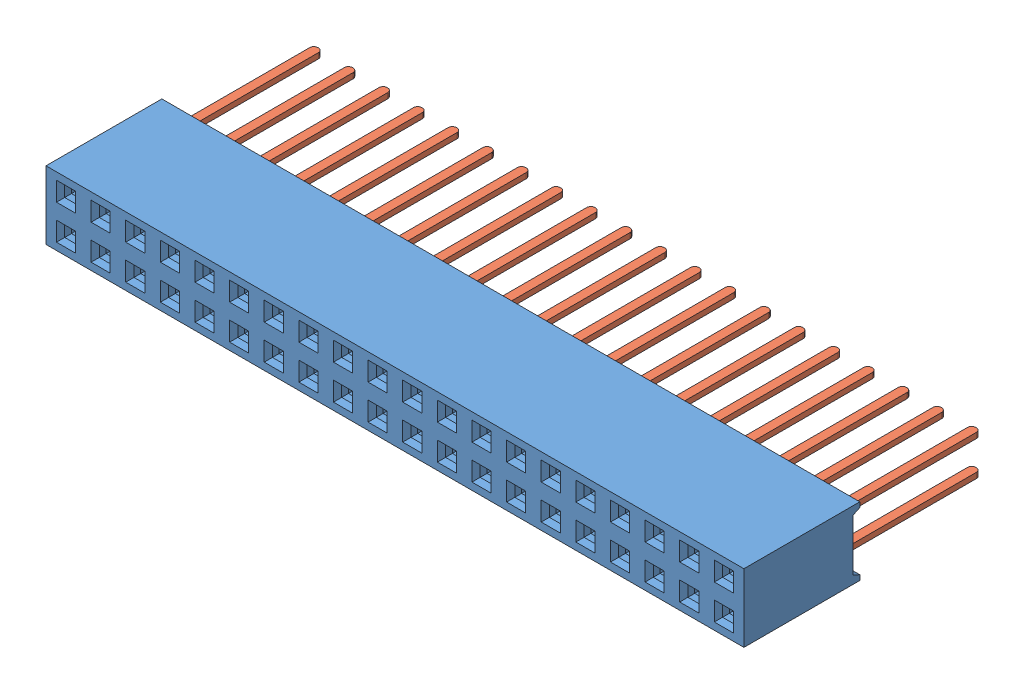
SolidWorks assembly 2.54-8.5-PC10, configuration 默认. Lengths in mm.
Overall size (51.2 5 18.5).
41 component instances, 2 part files, 2 mates.
Components (placement in the parent):
- 2.54排母-1: 2.54排母 [默认] at (35.9762 -74.8627 -4.25) size (51.2 5 8.5)
- Y端2.54-1: Y端2.54 [默认] at (-36.9112 -2.3944 0.1261) x (0 0 1) z (0 1 0) size (16.6 2.02 0.4)
- Y端2.54-2: Y端2.54 [默认] at (-34.3712 -2.3944 0.1261) x (0 0 1) z (0 1 0) size (16.6 2.02 0.4)
- Y端2.54-3: Y端2.54 [默认] at (-31.8312 -2.3944 0.1261) x (0 0 1) z (0 1 0) size (16.6 2.02 0.4)
- Y端2.54-4: Y端2.54 [默认] at (-29.2912 -2.3944 0.1261) x (0 0 1) z (0 1 0) size (16.6 2.02 0.4)
- Y端2.54-5: Y端2.54 [默认] at (-26.7512 -2.3944 0.1261) x (0 0 1) z (0 1 0) size (16.6 2.02 0.4)
- Y端2.54-6: Y端2.54 [默认] at (-24.2112 -2.3944 0.1261) x (0 0 1) z (0 1 0) size (16.6 2.02 0.4)
- Y端2.54-7: Y端2.54 [默认] at (-21.6712 -2.3944 0.1261) x (0 0 1) z (0 1 0) size (16.6 2.02 0.4)
- Y端2.54-8: Y端2.54 [默认] at (-19.1312 -2.3944 0.1261) x (0 0 1) z (0 1 0) size (16.6 2.02 0.4)
- Y端2.54-9: Y端2.54 [默认] at (-16.5912 -2.3944 0.1261) x (0 0 1) z (0 1 0) size (16.6 2.02 0.4)
- Y端2.54-10: Y端2.54 [默认] at (-14.0512 -2.3944 0.1261) x (0 0 1) z (0 1 0) size (16.6 2.02 0.4)
- Y端2.54-11: Y端2.54 [默认] at (-11.5112 -2.3944 0.1261) x (0 0 1) z (0 1 0) size (16.6 2.02 0.4)
- Y端2.54-12: Y端2.54 [默认] at (-8.9712 -2.3944 0.1261) x (0 0 1) z (0 1 0) size (16.6 2.02 0.4)
- Y端2.54-13: Y端2.54 [默认] at (-6.4312 -2.3944 0.1261) x (0 0 1) z (0 1 0) size (16.6 2.02 0.4)
- Y端2.54-14: Y端2.54 [默认] at (-3.8912 -2.3944 0.1261) x (0 0 1) z (0 1 0) size (16.6 2.02 0.4)
- Y端2.54-15: Y端2.54 [默认] at (-1.3512 -2.3944 0.1261) x (0 0 1) z (0 1 0) size (16.6 2.02 0.4)
- Y端2.54-16: Y端2.54 [默认] at (1.1888 -2.3944 0.1261) x (0 0 1) z (0 1 0) size (16.6 2.02 0.4)
- Y端2.54-17: Y端2.54 [默认] at (3.7288 -2.3944 0.1261) x (0 0 1) z (0 1 0) size (16.6 2.02 0.4)
- Y端2.54-18: Y端2.54 [默认] at (6.2688 -2.3944 0.1261) x (0 0 1) z (0 1 0) size (16.6 2.02 0.4)
- Y端2.54-19: Y端2.54 [默认] at (8.8088 -2.3944 0.1261) x (0 0 1) z (0 1 0) size (16.6 2.02 0.4)
- Y端2.54-20: Y端2.54 [默认] at (11.3488 -2.3944 0.1261) x (0 0 1) z (0 1 0) size (16.6 2.02 0.4)
- Y端2.54-22: Y端2.54 [默认] at (-36.9112 0.1456 0.1261) x (0 0 1) z (0 1 0) size (16.6 2.02 0.4)
- Y端2.54-23: Y端2.54 [默认] at (-34.3712 0.1456 0.1261) x (0 0 1) z (0 1 0) size (16.6 2.02 0.4)
- Y端2.54-24: Y端2.54 [默认] at (-31.8312 0.1456 0.1261) x (0 0 1) z (0 1 0) size (16.6 2.02 0.4)
- Y端2.54-25: Y端2.54 [默认] at (-29.2912 0.1456 0.1261) x (0 0 1) z (0 1 0) size (16.6 2.02 0.4)
- Y端2.54-26: Y端2.54 [默认] at (-26.7512 0.1456 0.1261) x (0 0 1) z (0 1 0) size (16.6 2.02 0.4)
- Y端2.54-27: Y端2.54 [默认] at (-24.2112 0.1456 0.1261) x (0 0 1) z (0 1 0) size (16.6 2.02 0.4)
- Y端2.54-28: Y端2.54 [默认] at (-21.6712 0.1456 0.1261) x (0 0 1) z (0 1 0) size (16.6 2.02 0.4)
- Y端2.54-29: Y端2.54 [默认] at (-19.1312 0.1456 0.1261) x (0 0 1) z (0 1 0) size (16.6 2.02 0.4)
- Y端2.54-30: Y端2.54 [默认] at (-16.5912 0.1456 0.1261) x (0 0 1) z (0 1 0) size (16.6 2.02 0.4)
- Y端2.54-31: Y端2.54 [默认] at (-14.0512 0.1456 0.1261) x (0 0 1) z (0 1 0) size (16.6 2.02 0.4)
- Y端2.54-32: Y端2.54 [默认] at (-11.5112 0.1456 0.1261) x (0 0 1) z (0 1 0) size (16.6 2.02 0.4)
- Y端2.54-33: Y端2.54 [默认] at (-8.9712 0.1456 0.1261) x (0 0 1) z (0 1 0) size (16.6 2.02 0.4)
- Y端2.54-34: Y端2.54 [默认] at (-6.4312 0.1456 0.1261) x (0 0 1) z (0 1 0) size (16.6 2.02 0.4)
- Y端2.54-35: Y端2.54 [默认] at (-3.8912 0.1456 0.1261) x (0 0 1) z (0 1 0) size (16.6 2.02 0.4)
- Y端2.54-36: Y端2.54 [默认] at (-1.3512 0.1456 0.1261) x (0 0 1) z (0 1 0) size (16.6 2.02 0.4)
- Y端2.54-37: Y端2.54 [默认] at (1.1888 0.1456 0.1261) x (0 0 1) z (0 1 0) size (16.6 2.02 0.4)
- Y端2.54-38: Y端2.54 [默认] at (3.7288 0.1456 0.1261) x (0 0 1) z (0 1 0) size (16.6 2.02 0.4)
- Y端2.54-39: Y端2.54 [默认] at (6.2688 0.1456 0.1261) x (0 0 1) z (0 1 0) size (16.6 2.02 0.4)
- Y端2.54-40: Y端2.54 [默认] at (8.8088 0.1456 0.1261) x (0 0 1) z (0 1 0) size (16.6 2.02 0.4)
- Y端2.54-41: Y端2.54 [默认] at (11.3488 0.1456 0.1261) x (0 0 1) z (0 1 0) size (16.6 2.02 0.4)
Mates (geometry in assembly coordinates):
- 重合1: coincident anti-aligned: plane of 2.54排母-1 through (-26.2723 -1.9944 3.45) normal (0 -1 0); plane of Y端2.54-1 through (-36.9112 -1.9944 0.1261) normal (0 1 0)
- 重合2: coincident aligned: plane of 2.54排母-1 through (35.9762 -74.8627 -3.75) normal (0 0 -1); plane of Y端2.54-1 through (-26.2636 -1.9944 -3.75) normal (0 0 -1)
